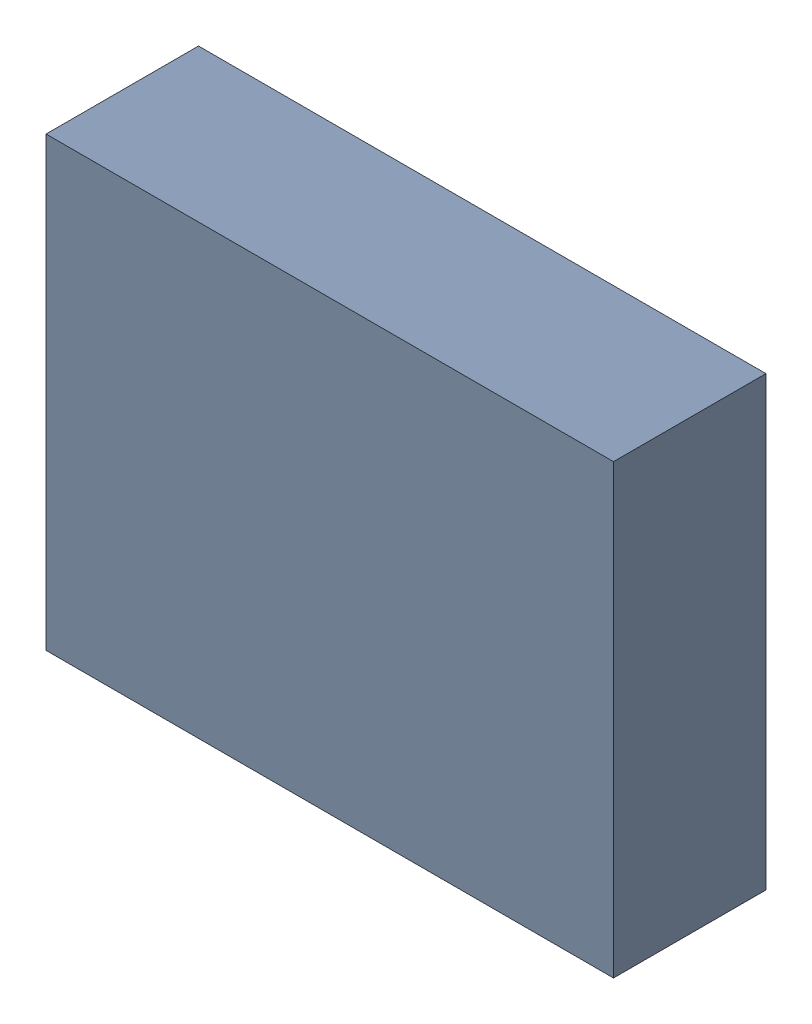
SolidWorks assembly PULL_I, configuration Default. Lengths in mm.
Overall size (3.35 2.64 0.9).
2 component instances, 1 part files, 0 mates.
Components (placement in the parent):
- 5920132160-1: 5920132160 [Default] at (46.25 33.75 0) size (3.35 2.64 0.9)
  - Extruded-1: Extruded [Default] at origin size (3.35 2.64 0.9)
